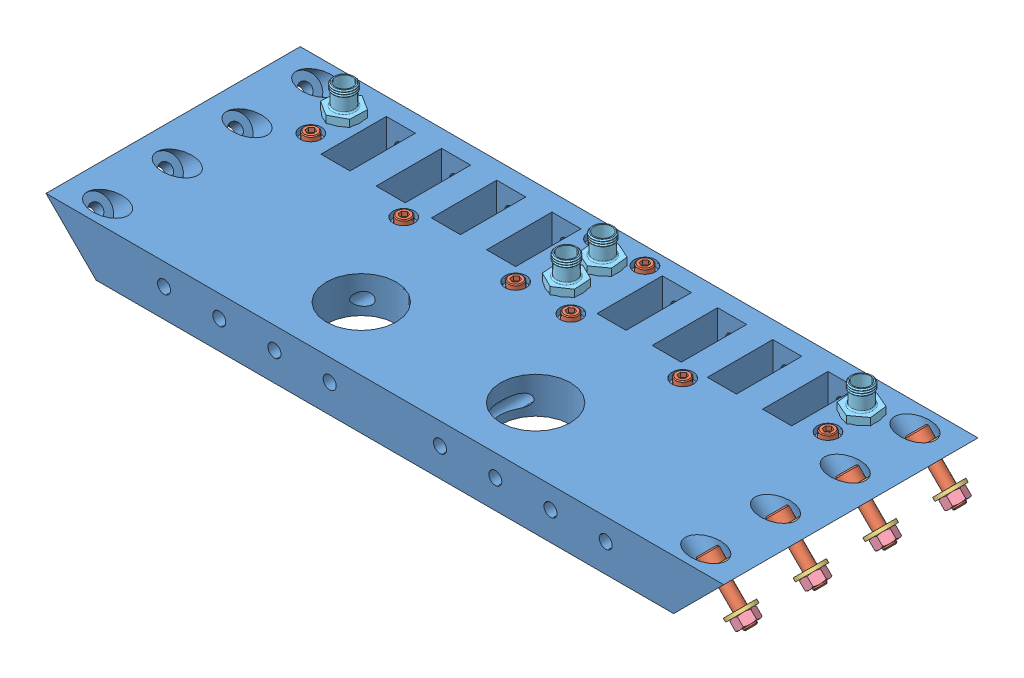
SolidWorks assembly joint_plate_assy_horz_sb_1108, configuration Default. Lengths in mm.
Overall size (476.94 58.38 175).
30 component instances, 5 part files, 13 mates.
Components (placement in the parent):
- joint_plate_horz_sb_1108-1: joint_plate_horz_sb_1108 [Default] at origin size (466.51 34.5 175)
- joint_plate_bolts_assy1x48-1: joint_plate_bolts_assy1x48 [Default] at (-0.2085 -212.2842 16) x (0.707107 -0.707107 0) z (0 0 1) size (43 18.8 162.8)
  - Socket Head Cap Screw_AM-1: Socket Head Cap Screw_AM [B18.3.1M - 8 x 1.25 x 35 Hex SHCS -- 35NHX] at (-21 313.5152 0) size (43 13 13)
  - flat washer narrow_am-1: flat washer narrow_am [B18.22M - Plain washer, 8 mm, narrow] at (-10.7 313.5152 0) size (2.3 18.8 18.8)
  - flat washer narrow_am-2: flat washer narrow_am [B18.22M - Plain washer, 8 mm, narrow] at (13.615 313.5152 0) size (2.3 18.8 18.8)
  - Hex Nut Style 1_AM-1: Hex Nut Style 1_AM [B18.2.4.1M - Hex nut, Style 1,  M8 x 1.25 --D-N] at (20.415 313.5152 0) x (0 0 -1) z (1 0 0) size (13 15.01 6.8)
  - Hex Nut Style 1_AM-2: Hex Nut Style 1_AM [B18.2.4.1M - Hex nut, Style 1,  M8 x 1.25 --D-N] at (20.415 313.5152 48) x (0 0 -1) z (1 0 0) size (13 15.01 6.8)
  - Hex Nut Style 1_AM-3: Hex Nut Style 1_AM [B18.2.4.1M - Hex nut, Style 1,  M8 x 1.25 --D-N] at (20.415 313.5152 96) x (0 0 -1) z (1 0 0) size (13 15.01 6.8)
  - Hex Nut Style 1_AM-4: Hex Nut Style 1_AM [B18.2.4.1M - Hex nut, Style 1,  M8 x 1.25 --D-N] at (20.415 313.5152 144) x (0 0 -1) z (1 0 0) size (13 15.01 6.8)
  - flat washer narrow_am-3: flat washer narrow_am [B18.22M - Plain washer, 8 mm, narrow] at (13.615 313.5152 48) size (2.3 18.8 18.8)
  - flat washer narrow_am-4: flat washer narrow_am [B18.22M - Plain washer, 8 mm, narrow] at (13.615 313.5152 96) size (2.3 18.8 18.8)
  - flat washer narrow_am-5: flat washer narrow_am [B18.22M - Plain washer, 8 mm, narrow] at (13.615 313.5152 144) size (2.3 18.8 18.8)
  - flat washer narrow_am-6: flat washer narrow_am [B18.22M - Plain washer, 8 mm, narrow] at (-10.7 313.5152 48) size (2.3 18.8 18.8)
  - flat washer narrow_am-7: flat washer narrow_am [B18.22M - Plain washer, 8 mm, narrow] at (-10.7 313.5152 96) size (2.3 18.8 18.8)
  - flat washer narrow_am-8: flat washer narrow_am [B18.22M - Plain washer, 8 mm, narrow] at (-10.7 313.5152 144) size (2.3 18.8 18.8)
  - Socket Head Cap Screw_AM-2: Socket Head Cap Screw_AM [B18.3.1M - 8 x 1.25 x 35 Hex SHCS -- 35NHX] at (-21 313.5152 48) size (43 13 13)
  - Socket Head Cap Screw_AM-3: Socket Head Cap Screw_AM [B18.3.1M - 8 x 1.25 x 35 Hex SHCS -- 35NHX] at (-21 313.5152 96) size (43 13 13)
  - Socket Head Cap Screw_AM-4: Socket Head Cap Screw_AM [B18.3.1M - 8 x 1.25 x 35 Hex SHCS -- 35NHX] at (-21 313.5152 144) size (43 13 13)
- water_adapter_b_1106-1: water_adapter_b_1106 [Default] at (178.13 0 25) x (0.802301 0 -0.59692) z (0 1 0) size (24 24 44)
- water_adapter_b_1106-2: water_adapter_b_1106 [Default] at (0 0 25) x (0.811534 0 -0.584305) z (0 1 0) size (24 24 44)
- water_adapter_b_1106-3: water_adapter_b_1106 [Default] at (0 0 50) x (0.831371 0 -0.555717) z (0 1 0) size (24 24 44)
- water_adapter_b_1106-4: water_adapter_b_1106 [Default] at (-178.13 0 25) x (0.885582 0 -0.464484) z (0 1 0) size (24 24 44)
- Socket Head Cap Screw_AM-1: Socket Head Cap Screw_AM [B18.3.1M - 6 x 1.0 x 35 Hex SHCS -- 24NHX] at (19 26.62 66) x (0 -1 0) z (-0.598139 0 -0.801393) size (41 10 10)
- Socket Head Cap Screw_AM-2: Socket Head Cap Screw_AM [B18.3.1M - 6 x 1.0 x 35 Hex SHCS -- 24NHX] at (-16 26.62 12) x (0 -1 0) z (-0.598139 0 -0.801393) size (41 10 10)
- Socket Head Cap Screw_AM-3: Socket Head Cap Screw_AM [B18.3.1M - 6 x 1.0 x 35 Hex SHCS -- 24NHX] at (16 26.62 12) x (0 -1 0) z (-0.598139 0 -0.801393) size (41 10 10)
- Socket Head Cap Screw_AM-4: Socket Head Cap Screw_AM [B18.3.1M - 6 x 1.0 x 35 Hex SHCS -- 24NHX] at (96 26.62 66) x (0 -1 0) z (-0.598139 0 -0.801393) size (41 10 10)
- Socket Head Cap Screw_AM-5: Socket Head Cap Screw_AM [B18.3.1M - 6 x 1.0 x 35 Hex SHCS -- 24NHX] at (-96 26.62 66) x (0 -1 0) z (-0.598139 0 -0.801393) size (41 10 10)
- Socket Head Cap Screw_AM-6: Socket Head Cap Screw_AM [B18.3.1M - 6 x 1.0 x 35 Hex SHCS -- 24NHX] at (178 26.62 48) x (0 -1 0) z (-0.598139 0 -0.801393) size (41 10 10)
- Socket Head Cap Screw_AM-7: Socket Head Cap Screw_AM [B18.3.1M - 6 x 1.0 x 35 Hex SHCS -- 24NHX] at (-178 26.62 48) x (0 -1 0) z (-0.598139 0 -0.801393) size (41 10 10)
- Socket Head Cap Screw_AM-8: Socket Head Cap Screw_AM [B18.3.1M - 6 x 1.0 x 35 Hex SHCS -- 24NHX] at (-19 26.62 66) x (0 -1 0) z (-0.598139 0 -0.801393) size (41 10 10)
Mates (geometry in assembly coordinates):
- Coincident1: coincident aligned: plane of joint_plate_horz_sb_1108-1 through (-208.2574 0 175) normal (0 -1 0); plane of water_adapter_b_1106-3 through (0 0 50) normal (0 -1 0)
- Coincident2: coincident aligned: plane of joint_plate_horz_sb_1108-1 through (-208.2574 0 175) normal (0 -1 0); plane of water_adapter_b_1106-2 through (0 0 25) normal (0 -1 0)
- Coincident3: coincident aligned: plane of joint_plate_horz_sb_1108-1 through (-208.2574 0 175) normal (0 -1 0); plane of water_adapter_b_1106-1 through (178.13 0 25) normal (0 -1 0)
- Coincident4: coincident aligned: plane of joint_plate_horz_sb_1108-1 through (-208.2574 0 175) normal (0 -1 0); plane of water_adapter_b_1106-4 through (-178.13 0 25) normal (0 -1 0)
- Concentric1: concentric anti-aligned: cylinder of joint_plate_horz_sb_1108-1 through (178.13 25 25) axis (0 1 0) radius 11; cylinder of water_adapter_b_1106-1 through (178.13 30 25) axis (0 -1 0) radius 12
- Concentric2: concentric anti-aligned: cylinder of joint_plate_horz_sb_1108-1 through (0 25 50) axis (0 1 0) radius 11; cylinder of water_adapter_b_1106-3 through (0 30 50) axis (0 -1 0) radius 12
- Concentric3: concentric anti-aligned: cylinder of joint_plate_horz_sb_1108-1 through (0 25 25) axis (0 1 0) radius 11; cylinder of water_adapter_b_1106-2 through (0 30 25) axis (0 -1 0) radius 12
- Concentric4: concentric aligned: cylinder of joint_plate_horz_sb_1108-1 through (-178.13 25 25) axis (0 1 0) radius 11; cylinder of water_adapter_b_1106-4 through (-178.13 0 25) axis (0 1 0) radius 6
- Coincident5: coincident anti-aligned: plane of joint_plate_horz_sb_1108-1 through (213.9142 16.9706 160) normal (-0.707107 0.707107 0); plane of joint_plate_bolts_assy1x48-1/flat washer narrow_am-8 through (217.1386 20.195 160) normal (0.707107 -0.707107 0)
- Concentric5: concentric anti-aligned: cylinder of joint_plate_horz_sb_1108-1 through (-13.6863 244.5711 160) axis (0.707107 -0.707107 0) radius 4.5; cylinder of joint_plate_bolts_assy1x48-1/Socket Head Cap Screw_AM-4 through (184.1804 46.7044 160) axis (-0.707107 0.707107 0) radius 4
- Concentric6: concentric anti-aligned: cylinder of joint_plate_horz_sb_1108-1 through (-13.6863 244.5711 16) axis (0.707107 -0.707107 0) radius 4.5; cylinder of joint_plate_bolts_assy1x48-1/Socket Head Cap Screw_AM-1 through (184.1804 46.7044 16) axis (-0.707107 0.707107 0) radius 4
- Coincident6: coincident anti-aligned: plane of joint_plate_horz_sb_1108-1 through (22.3 20.62 66) normal (0 1 0); plane of Socket Head Cap Screw_AM-1 through (14.993 20.62 68.9907) normal (0 -1 0)
- Concentric7: concentric aligned: cylinder of joint_plate_horz_sb_1108-1 through (19 25 66) axis (0 1 0) radius 3.3; cylinder of Socket Head Cap Screw_AM-1 through (19 58.37 66) axis (0 1 0) radius 3
